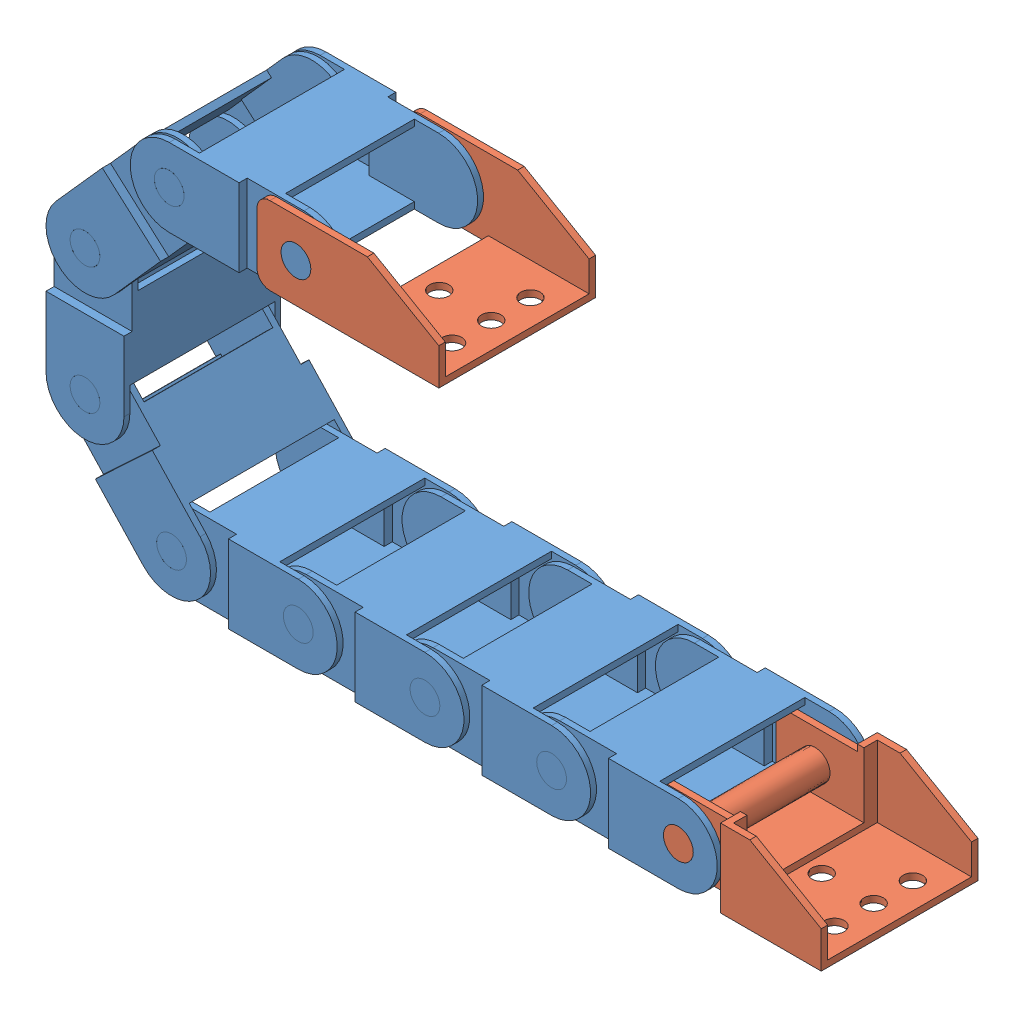
SolidWorks assembly e-chain cable carrier, configuration Default. Lengths in mm.
Overall size (121.81 65.25 24.13).
10 component instances, 2 part files, 18 mates.
Components (placement in the parent):
- e-chain cable carrier link 05-4-038-0-2: e-chain cable carrier link 05-4-038-0 [Default] at (-72.7484 -6.705 37.8592) size (31.5 12 24.13)
- e-chain cable carrier link 05-4-038-0-3: e-chain cable carrier link 05-4-038-0 [Default] at (-92.2484 -6.705 37.8592) size (31.5 12 24.13)
- e-chain cable carrier link 05-4-038-0-4: e-chain cable carrier link 05-4-038-0 [Default] at (-111.7484 -6.705 37.8592) size (31.5 12 24.13)
- e-chain cable carrier link 05-4-038-0-5: e-chain cable carrier link 05-4-038-0 [Default] at (-131.2484 -6.705 37.8592) size (31.5 12 24.13)
- e-chain cable carrier link 05-4-038-0-6: e-chain cable carrier link 05-4-038-0 [Default] at (-150.7484 -6.705 37.8592) x (0.683581 -0.729875 0) z (0 0 1) size (31.5 12 24.13)
- e-chain cable carrier link 05-4-038-0-7: e-chain cable carrier link 05-4-038-0 [Default] at (-164.0782 7.5276 37.8592) x (0 -1 0) z (0 0 1) size (31.5 12 24.13)
- e-chain cable carrier link 05-4-038-0-8: e-chain cable carrier link 05-4-038-0 [Default] at (-164.0782 27.0276 37.8592) x (-0.665043 -0.746805 0) z (0 0 1) size (31.5 12 24.13)
- e-chain cable carrier link 05-4-038-0-9: e-chain cable carrier link 05-4-038-0 [Default] at (-151.1099 41.5903 37.8592) x (-1 0 0) z (0 0 1) size (31.5 12 24.13)
- e-chain cable carrier mounting bracket 050-20-12-1: e-chain cable carrier mounting bracket 050-20-12 [Default] at (-131.6099 41.5903 37.8592) size (28 12 24.13)
- e-chain cable carrier mounting bracket 050-20-12-2: e-chain cable carrier mounting bracket 050-20-12 [fixed bracket] at (-72.7484 -6.705 37.8592) size (28 12 24.13)
Mates (geometry in assembly coordinates):
- Concentric2: concentric aligned: cylinder of e-chain cable carrier link 05-4-038-0-2 through (-92.2484 -6.705 56.4296) axis (0 0 -1) radius 2.3; cylinder of e-chain cable carrier link 05-4-038-0-3 through (-92.2484 -6.705 49.9242) axis (0 0 -1) radius 2.3
- Coincident2: coincident aligned: plane of e-chain cable carrier link 05-4-038-0-2 through (-72.7484 -6.705 49.9242) normal (0 0 1); plane of e-chain cable carrier link 05-4-038-0-3 through (-92.2484 -6.705 49.9242) normal (0 0 1)
- Concentric3: concentric aligned: cylinder of e-chain cable carrier link 05-4-038-0-3 through (-111.7484 -6.705 56.4296) axis (0 0 -1) radius 2.3; cylinder of e-chain cable carrier link 05-4-038-0-4 through (-111.7484 -6.705 49.9242) axis (0 0 -1) radius 2.3
- Coincident3: coincident aligned: plane of e-chain cable carrier link 05-4-038-0-3 through (-92.2484 -6.705 49.9242) normal (0 0 1); plane of e-chain cable carrier link 05-4-038-0-4 through (-111.7484 -6.705 49.9242) normal (0 0 1)
- Concentric4: concentric aligned: cylinder of e-chain cable carrier link 05-4-038-0-4 through (-131.2484 -6.705 56.4296) axis (0 0 -1) radius 2.3; cylinder of e-chain cable carrier link 05-4-038-0-5 through (-131.2484 -6.705 49.9242) axis (0 0 -1) radius 2.3
- Coincident4: coincident aligned: plane of e-chain cable carrier link 05-4-038-0-4 through (-111.7484 -6.705 49.9242) normal (0 0 1); plane of e-chain cable carrier link 05-4-038-0-5 through (-131.2484 -6.705 49.9242) normal (0 0 1)
- Concentric5: concentric aligned: cylinder of e-chain cable carrier link 05-4-038-0-5 through (-150.7484 -6.705 56.4296) axis (0 0 -1) radius 2.3; cylinder of e-chain cable carrier link 05-4-038-0-6 through (-150.7484 -6.705 49.9242) axis (0 0 -1) radius 2.3
- Coincident5: coincident aligned: plane of e-chain cable carrier link 05-4-038-0-5 through (-131.2484 -6.705 49.9242) normal (0 0 1); plane of e-chain cable carrier link 05-4-038-0-6 through (-150.7484 -6.705 49.9242) normal (0 0 1)
- Concentric6: concentric aligned: cylinder of e-chain cable carrier link 05-4-038-0-6 through (-164.0782 7.5276 56.4296) axis (0 0 -1) radius 2.3; cylinder of e-chain cable carrier link 05-4-038-0-7 through (-164.0782 7.5276 49.9242) axis (0 0 -1) radius 2.3
- Coincident6: coincident aligned: plane of e-chain cable carrier link 05-4-038-0-6 through (-150.7484 -6.705 49.9242) normal (0 0 1); plane of e-chain cable carrier link 05-4-038-0-7 through (-164.0782 7.5276 49.9242) normal (0 0 1)
- Concentric7: concentric aligned: cylinder of e-chain cable carrier link 05-4-038-0-7 through (-164.0782 27.0276 56.4296) axis (0 0 -1) radius 2.3; cylinder of e-chain cable carrier link 05-4-038-0-8 through (-164.0782 27.0276 49.9242) axis (0 0 -1) radius 2.3
- Coincident7: coincident aligned: plane of e-chain cable carrier link 05-4-038-0-7 through (-164.0782 7.5276 49.9242) normal (0 0 1); plane of e-chain cable carrier link 05-4-038-0-8 through (-164.0782 27.0276 49.9242) normal (0 0 1)
- Concentric8: concentric aligned: cylinder of e-chain cable carrier link 05-4-038-0-8 through (-151.1099 41.5903 56.4296) axis (0 0 -1) radius 2.3; cylinder of e-chain cable carrier link 05-4-038-0-9 through (-151.1099 41.5903 49.9242) axis (0 0 -1) radius 2.3
- Coincident8: coincident aligned: plane of e-chain cable carrier link 05-4-038-0-8 through (-164.0782 27.0276 49.9242) normal (0 0 1); plane of e-chain cable carrier link 05-4-038-0-9 through (-151.1099 41.5903 49.9242) normal (0 0 1)
- Concentric9: concentric aligned: cylinder of e-chain cable carrier link 05-4-038-0-9 through (-131.6099 41.5903 56.4296) axis (0 0 -1) radius 2.3; cylinder of e-chain cable carrier mounting bracket 050-20-12-1 through (-131.6099 41.5903 49.9242) axis (0 0 -1) radius 2.3
- Concentric10: concentric anti-aligned: cylinder of e-chain cable carrier link 05-4-038-0-2 through (-72.7484 -6.705 49.9242) axis (0 0 -1) radius 2.3; cylinder of e-chain cable carrier mounting bracket 050-20-12-2 through (-72.7484 -6.705 19.2888) axis (0 0 1) radius 2.3
- Coincident10: coincident aligned: plane of e-chain cable carrier link 05-4-038-0-2 through (-72.7484 -6.705 49.9242) normal (0 0 1); plane of e-chain cable carrier mounting bracket 050-20-12-2 through (-72.7484 -6.705 49.9242) normal (0 0 1)
- Coincident18: coincident aligned: plane of e-chain cable carrier link 05-4-038-0-9 through (-151.1099 41.5903 49.9242) normal (0 0 1); plane of e-chain cable carrier mounting bracket 050-20-12-1 through (-131.6099 41.5903 49.9242) normal (0 0 1)
